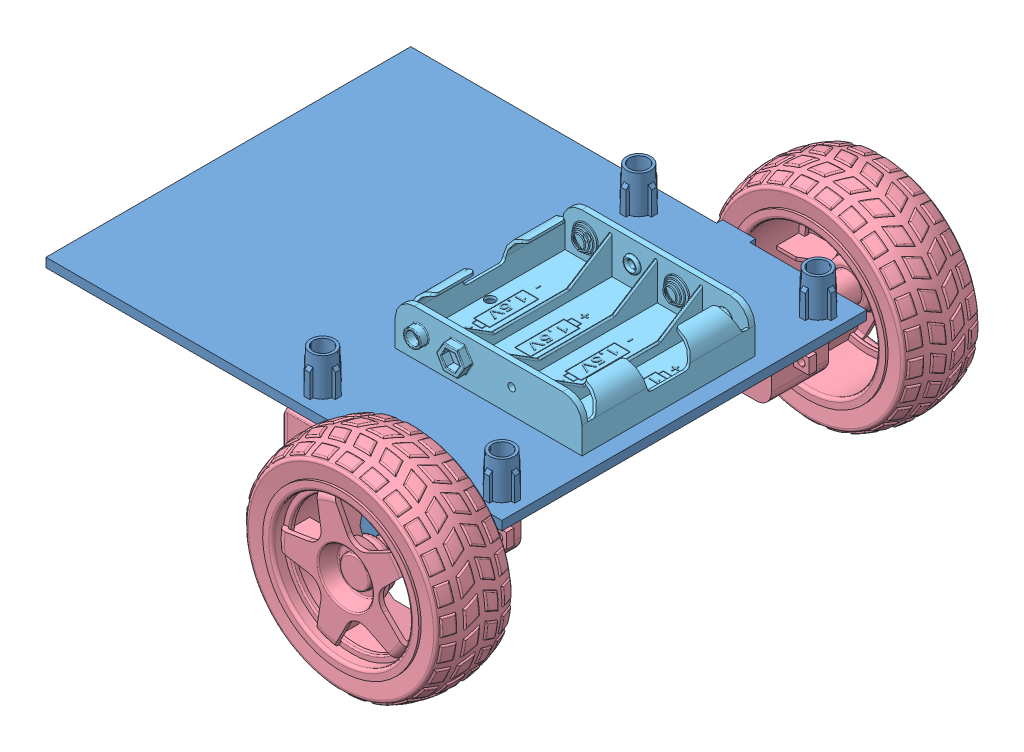
SolidWorks assembly main2, configuration Default. Lengths in mm.
Overall size (160.78 69.55 178.6).
8 component instances, 5 part files, 2 mates.
Components (placement in the parent):
- main1-1: main1 [Default] at (-18.5074 6.649 48.7257) size (160.78 69.55 178.6)
  - Part1-1: Part1 [Default] at (-6.1553 78.7696 167.0022) size (150 37.55 124)
  - caster-1: caster [Default] at (47.2378 72.3089 131.4385) x (0 0 -1) z (-1 0 0) size (44 45 28)
    - cup-1: cup [Default] at (19.4271 17.5393 31.8931) size (44 38.22 28)
    - sphere-1: sphere [Default] at (14.2695 30.5393 38.0085) size (16 16 16)
  - motor+wheel+pad-1: motor+wheel+pad [Default] at (-23.0627 -16.2309 210.4693) x (0 0 -1) z (1 0 0) size (57.2 68.99 89.08)
  - motor+wheel+pad-2: motor+wheel+pad [Default] at (-23.0627 151.4701 3.5351) x (0 0 1) z (1 0 0) size (57.2 68.99 89.08)
- User Library-R6_AA_UM3-1_5V_holder4AA-2: User Library-R6_AA_UM3-1_5V_holder4AA [4AA] at (89.3972 88.4185 155.728) x (0 0 1) z (0 1 0) size (59.56 61.47 15.11)
Mates (geometry in assembly coordinates):
- Concentric1: concentric anti-aligned: circle of main1-1/Part1-1; circle of User Library-R6_AA_UM3-1_5V_holder4AA-2
- Coincident1: coincident anti-aligned: plane of main1-1/Part1-1 through (-24.6628 88.4185 215.728) normal (0 1 0); plane of User Library-R6_AA_UM3-1_5V_holder4AA-2 through (58.6632 88.4185 127.28) normal (0 -1 0)
